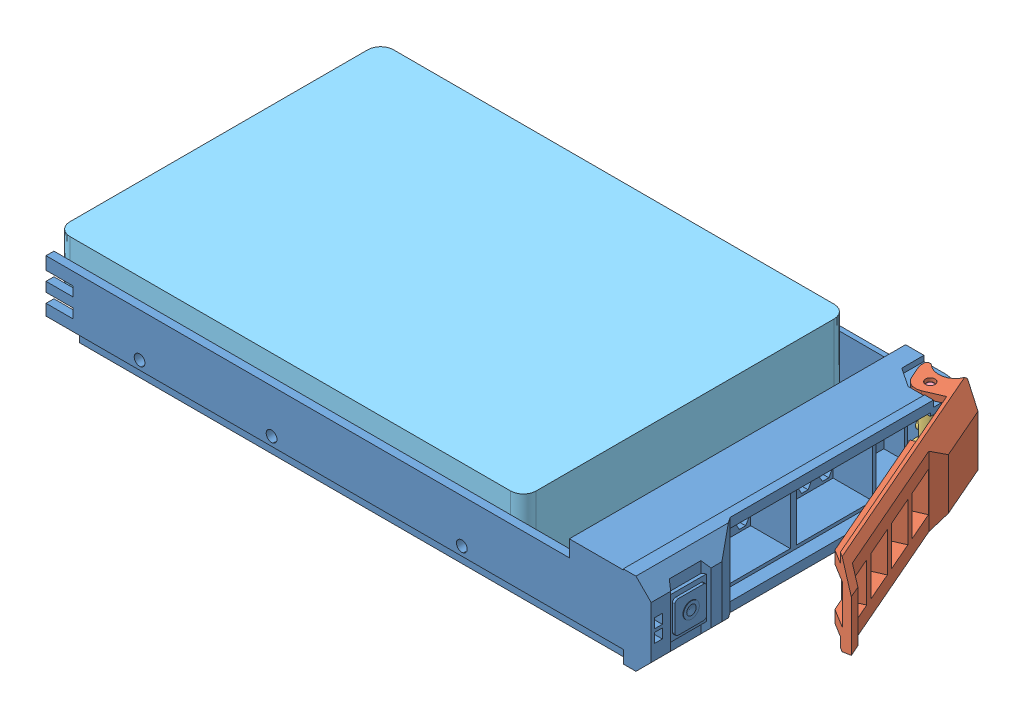
SolidWorks assembly 支架和硬盘装配体, configuration 默认. Lengths in mm.
Overall size (220.6 27 110.23).
9 component instances, 7 part files, 6 mates.
Components (placement in the parent):
- 硬盘托架装配体-1: 硬盘托架装配体 [默认] at (-20.5726 -30.1611 31.7113) size (220.6 26 110.23)
  - 硬盘托架-1: 硬盘托架 [默认] at (-103.8436 -9.5073 191) size (191 26 106)
  - 硬盘托架把手-3: 硬盘托架把手 [默认] at (108.4968 -9.5073 214.2918) x (0.917212 0 -0.3984) z (0 -1 0) size (16 83.88 26)
  - 硬盘托架轴-1: 硬盘托架轴 [默认] at (75.4564 -5.5073 144.5) size (9 17.5 9)
  - 硬盘托架插销-2: 硬盘托架插销 [默认] at (75.4564 -9.3073 144.5) size (2.8 25 2.8)
- 3_5寸硬盘整体-1: 3_5寸硬盘整体 [默认] at (-49.9162 -39.1684 222.2113) x (-1 0 0) z (0 0 -1) size (147 26.5 102) (hidden)
- 3_5寸硬盘装配体-1: 3_5寸硬盘装配体 [默认] at (-58.0623 -27.7778 369.2113) x (-1 0 0) z (0 0 -1) size (147 26.5 102)
  - 3_5寸硬盘-1: 3_5寸硬盘 [默认] at (-8.1461 -11.3906 147) size (147 26.5 102)
  - 3_5寸硬盘主板-1: 3_5寸硬盘主板 [默认] at (-0.6461 -10.3906 193.5) size (66 8.5 81)
Mates (geometry in assembly coordinates):
- 重合1: coincident aligned: axis of 硬盘托架装配体-1/硬盘托架-1 through (6.6838 -32.9184 273.2113) axis (0 0 1); axis of 3_5寸硬盘整体-1 through (6.6838 -32.9184 269.7113) axis (0 0 1)
- 重合2: coincident aligned: axis of 硬盘托架装配体-1/硬盘托架-1 through (-53.3062 -32.9184 273.2113) axis (0 0 1); axis of 3_5寸硬盘整体-1 through (-53.3062 -32.9184 269.7113) axis (0 0 1)
- 重合3: coincident anti-aligned: plane of 硬盘托架装配体-1/硬盘托架-1 through (144.5261 -19.1684 273.2113) normal (0 0 -1); plane of 3_5寸硬盘整体-1 through (23.5838 -12.6684 273.2113) normal (0 0 1)
- 重合4: coincident aligned: axis of 硬盘托架装配体-1/硬盘托架-1 through (6.6838 -32.9184 273.2113) axis (0 0 1); axis of 3_5寸硬盘装配体-1/3_5寸硬盘-1 through (6.6838 -32.9184 269.9113) axis (0 0 1)
- 重合5: coincident aligned: axis of 硬盘托架装配体-1/硬盘托架-1 through (-53.3062 -32.9184 273.2113) axis (0 0 1); axis of 3_5寸硬盘装配体-1/3_5寸硬盘-1 through (-53.3062 -32.9184 269.9113) axis (0 0 1)
- 重合6: coincident anti-aligned: plane of 硬盘托架装配体-1/硬盘托架-1 through (144.5261 -19.1684 273.2113) normal (0 0 -1); plane of 3_5寸硬盘装配体-1/3_5寸硬盘-1 through (23.5838 -12.6684 273.2113) normal (0 0 1)
